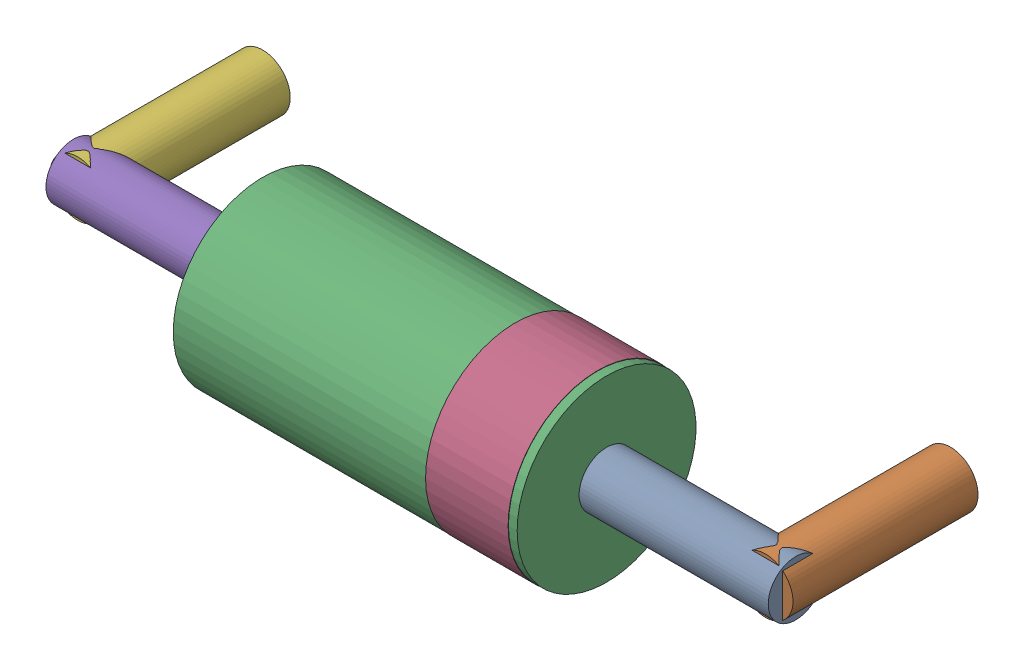
SolidWorks assembly D6, configuration Default. Lengths in mm.
Overall size (10.8 2.61 3.81).
12 component instances, 6 part files, 0 mates.
Components (placement in the parent):
- -1733042672-1: -1733042672 [Default] at (514.2502 282.9977 1.5) x (0 0 -1) z (-1 0 0) size (0.8 0.8 2.75)
  - Cylinder-1: Cylinder [Default] at origin size (0.8 0.8 2.75)
- -1733042992-1: -1733042992 [Default] at (513.9999 282.9999 -1) x (-1 0 0) z (0 0 1) size (0.8 0.8 2.69)
  - Cylinder_2-1: Cylinder_2 [Default] at origin size (0.8 0.8 2.69)
- -1733042432-1: -1733042432 [Default] at (511.5001 282.9975 1.5) x (0 0 -1) z (-1 0 0) size (2.6 2.6 5)
  - Cylinder_3-1: Cylinder_3 [Default] at origin size (2.6 2.6 5)
- -1733042152-1: -1733042152 [Default] at (511.3731 282.9976 1.5) x (0 0 -1) z (-1 0 0) size (2.61 2.61 1.2)
  - Cylinder_4-1: Cylinder_4 [Default] at origin size (2.61 2.61 1.2)
- -1733041072-1: -1733041072 [Default] at (503.7497 283.0023 1.5) x (0 0 -1) z (1 0 0) size (0.8 0.8 2.75)
  - Cylinder_5-1: Cylinder_5 [Default] at origin size (0.8 0.8 2.75)
- -1733041192-1: -1733041192 [Default] at (504.0001 283.0001 -1) x (1 0 0) z (0 0 1) size (0.8 0.8 2.69)
  - Cylinder_6-1: Cylinder_6 [Default] at origin size (0.8 0.8 2.69)
